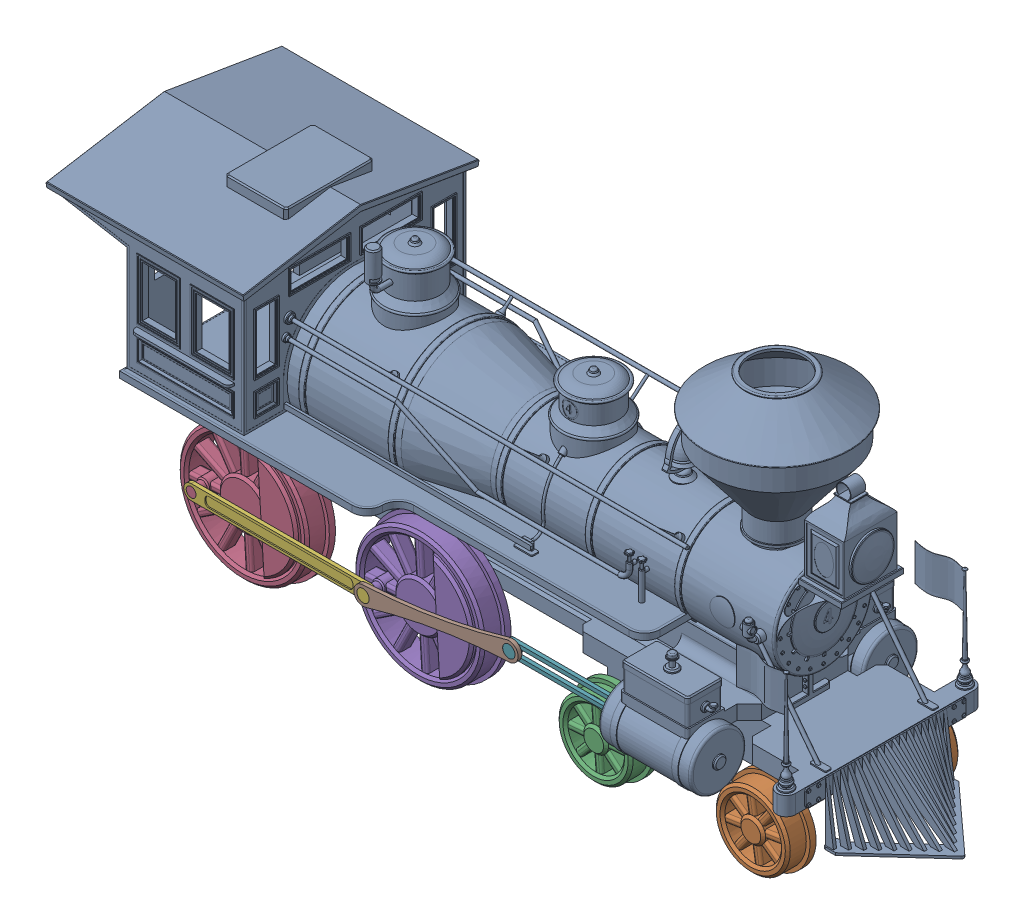
SolidWorks assembly Locomotive Assembly, configuration Default. Lengths in mm.
Overall size (649.03 311.03 191.34).
11 component instances, 6 part files, 27 mates.
Components (placement in the parent):
- Magic Kingdom Locomotive-1: Magic Kingdom Locomotive [Default] at (-90.9161 147.138 199.4576) size (649.03 272 191.34)
- Wheels Front-1: Wheels Front [Default] at (708.1738 327.9737 254.4576) x (-0.587646 -0.809118 0) z (0 0 1) size (66 66 140)
- Wheels Front-2: Wheels Front [Default] at (20.2721 388.2461 254.4576) x (0.759766 -0.650197 0) z (0 0 1) size (66 66 140)
- Wheels Back-1: Wheels Back [Default] at (-96.4231 142.2788 254.4576) x (0.998017 0.062939 0) z (0 0 1) size (111 111 158)
- Wheels Back-2: Wheels Back [Default] at (46.0769 142.2788 254.4576) x (0.998017 0.062939 0) z (0 0 1) size (111 111 158)
- Linkage 1-1: Linkage 1 [Default] at (-49.8332 75.0778 275.4576) size (154.5 12 6)
- Linkage 3-1: Linkage 3 [Default] at (250.9782 95.138 275.4576) size (92 12 6)
- Linkage 2-1: Linkage 2 [Default] at (92.6668 75.0778 278.4576) x (0.985928 0.167168 0) z (0 0 1) size (135 15 3)
- Linkage 1-2: Linkage 1 [Default] at (-49.8332 75.0778 123.4576) x (1 0 0) z (0 0 -1) size (154.5 12 6)
- Linkage 2-2: Linkage 2 [Default] at (92.6668 75.0778 117.4576) x (0.985928 0.167168 0) z (0 0 1) size (135 15 3)
- Linkage 3-2: Linkage 3 [Default] at (250.9782 95.138 123.4576) x (1 0 0) z (0 0 -1) size (92 12 6)
Mates (geometry in assembly coordinates):
- Concentric1: concentric aligned: cylinder of Magic Kingdom Locomotive-1 through (395.3339 54.638 234.4576) axis (0 0 1) radius 5; cylinder of Wheels Front-1 through (395.3339 54.638 199.4576) axis (0 0 1) radius 5
- Width1: width aligned: plane of Wheels Front-1 through (395.3339 54.638 249.4576) normal (0 0 -1); plane of Magic Kingdom Locomotive-1 through (395.3339 54.638 149.4576) normal (0 0 1); plane of Wheels Front-1 through (-90.9161 147.138 234.4576) normal (0 0 -1); plane of Magic Kingdom Locomotive-1 through (-90.9161 147.138 164.4576) normal (0 0 1)
- Concentric2: concentric aligned: cylinder of Magic Kingdom Locomotive-1 through (267.8339 54.638 234.4576) axis (0 0 1) radius 5; cylinder of Wheels Front-2 through (267.8339 54.638 199.4576) axis (0 0 1) radius 5
- Coincident1: coincident aligned: plane of Wheels Front-1 through (708.1738 327.9737 269.4576) normal (0 0 1); plane of Wheels Front-2 through (20.2721 388.2461 269.4576) normal (0 0 1)
- Concentric3: concentric aligned: cylinder of Magic Kingdom Locomotive-1 through (-17.1661 77.138 234.4576) axis (0 0 1) radius 5; cylinder of Wheels Back-1 through (-17.1661 77.138 199.4576) axis (0 0 1) radius 5
- Coincident2: coincident aligned: plane of Wheels Front-2 through (20.2721 388.2461 269.4576) normal (0 0 1); plane of Wheels Back-1 through (-96.4231 142.2788 269.4576) normal (0 0 1)
- Concentric4: concentric aligned: cylinder of Magic Kingdom Locomotive-1 through (125.3339 77.138 234.4576) axis (0 0 1) radius 5; cylinder of Wheels Back-2 through (125.3339 77.138 199.4576) axis (0 0 1) radius 5
- Coincident3: coincident aligned: plane of Wheels Back-1 through (-96.4231 142.2788 269.4576) normal (0 0 1); plane of Wheels Back-2 through (46.0769 142.2788 269.4576) normal (0 0 1)
- Concentric5: concentric aligned: cylinder of Wheels Back-1 through (-49.8332 75.0778 278.4576) axis (0 0 -1) radius 4; cylinder of Linkage 1-1 through (-49.8332 75.0778 278.4576) axis (0 0 -1) radius 4
- Coincident4: coincident aligned: plane of Wheels Back-1 through (-49.8332 75.0778 278.4576) normal (0 0 1); plane of Linkage 1-1 through (-49.8332 75.0778 278.4576) normal (0 0 1)
- Concentric6: concentric aligned: cylinder of Wheels Back-2 through (92.6668 75.0778 278.4576) axis (0 0 -1) radius 4; cylinder of Linkage 1-1 through (92.6668 75.0778 281.4576) axis (0 0 -1) radius 5
- Parallel1: parallel aligned: plane of Magic Kingdom Locomotive-1 through (309.0839 147.138 104.4576) normal (0 1 0); plane of Linkage 1-1 through (-49.8332 81.0778 278.4576) normal (0 1 0)
- Coincident6: coincident anti-aligned: plane of Magic Kingdom Locomotive-1 through (364.0839 101.138 275.4576) normal (0 -1 0); plane of Linkage 3-1 through (204.9782 101.138 278.4576) normal (0 1 0)
- Coincident7: coincident anti-aligned: plane of Magic Kingdom Locomotive-1 through (364.0839 89.138 278.4576) normal (0 0 -1); plane of Linkage 3-1 through (250.9782 95.138 278.4576) normal (0 0 1)
- Concentric7: concentric aligned: cylinder of Linkage 1-1 through (92.6668 75.0778 281.4576) axis (0 0 -1) radius 5; cylinder of Linkage 2-1 through (92.6668 75.0778 281.4576) axis (0 0 -1) radius 5
- Coincident8: coincident aligned: plane of Linkage 1-1 through (92.6668 75.0778 281.4576) normal (0 0 1); plane of Linkage 2-1 through (92.6668 75.0778 281.4576) normal (0 0 1)
- Concentric8: concentric anti-aligned: cylinder of Linkage 3-1 through (210.9782 95.138 261.3154) axis (0 0 1) radius 5; cylinder of Linkage 2-1 through (210.9782 95.138 281.4576) axis (0 0 -1) radius 5
- Concentric9: concentric aligned: cylinder of Wheels Back-1 through (-49.8332 75.0778 120.4576) axis (0 0 1) radius 4; cylinder of Linkage 1-2 through (-49.8332 75.0778 120.4576) axis (0 0 1) radius 4
- Concentric10: concentric aligned: cylinder of Wheels Back-2 through (92.6668 75.0778 120.4576) axis (0 0 1) radius 4; cylinder of Linkage 1-2 through (92.6668 75.0778 117.4576) axis (0 0 1) radius 5
- Coincident9: coincident aligned: plane of Wheels Back-1 through (-49.8332 75.0778 120.4576) normal (0 0 -1); plane of Linkage 1-2 through (-49.8332 75.0778 120.4576) normal (0 0 -1)
- Concentric11: concentric anti-aligned: cylinder of Linkage 1-2 through (92.6668 75.0778 117.4576) axis (0 0 1) radius 5; cylinder of Linkage 2-2 through (92.6668 75.0778 120.4576) axis (0 0 -1) radius 5
- Coincident10: coincident aligned: plane of Linkage 1-2 through (92.6668 75.0778 117.4576) normal (0 0 -1); plane of Linkage 2-2 through (92.6668 75.0778 117.4576) normal (0 0 -1)
- Coincident11: coincident anti-aligned: plane of Magic Kingdom Locomotive-1 through (364.0839 89.138 120.4576) normal (0 0 1); plane of Linkage 3-2 through (250.9782 95.138 120.4576) normal (0 0 -1)
- Coincident12: coincident anti-aligned: plane of Magic Kingdom Locomotive-1 through (364.0839 101.138 123.4576) normal (0 -1 0); plane of Linkage 3-2 through (204.9782 101.138 120.4576) normal (0 1 0)
- Concentric12: concentric aligned: cylinder of Linkage 2-2 through (210.9782 95.138 120.4576) axis (0 0 -1) radius 5; cylinder of Linkage 3-2 through (210.9782 95.138 137.5997) axis (0 0 -1) radius 5
- GearMate1: gear = 60 : 105 mm: cylinder of Wheels Back-2 through (125.3339 77.138 269.4576) axis (0 0 -1) radius 52.5; cylinder of Wheels Front-2 through (267.8339 54.638 269.4576) axis (0 0 -1) radius 30
- GearMate2: gear = 60 : 60 mm: cylinder of Wheels Front-2 through (267.8339 54.638 269.4576) axis (0 0 -1) radius 30; cylinder of Wheels Front-1 through (395.3339 54.638 269.4576) axis (0 0 -1) radius 30
